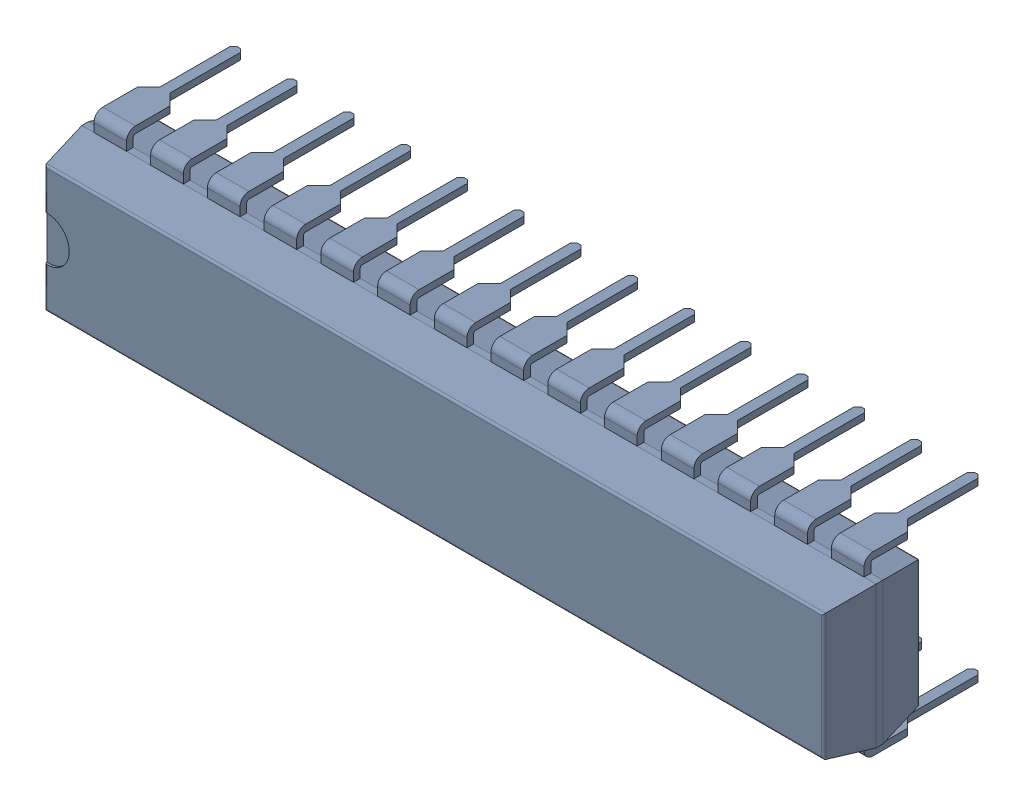
SolidWorks assembly U3, configuration Défaut. Lengths in mm.
Overall size (35.56 7.92 7.75).
2 component instances, 1 part files, 0 mates.
Components (placement in the parent):
- Open CASCADE STEP translator 6.8 1.2.1-1: Open CASCADE STEP translator 6.8 1.2.1 [Défaut] at origin size (35.56 7.92 7.75)
  - Body_1-1: Body_1 [Défaut] at (16.5 3.8 0) x (0 1 0) z (1 0 0) size (7.92 7.75 35.56)
